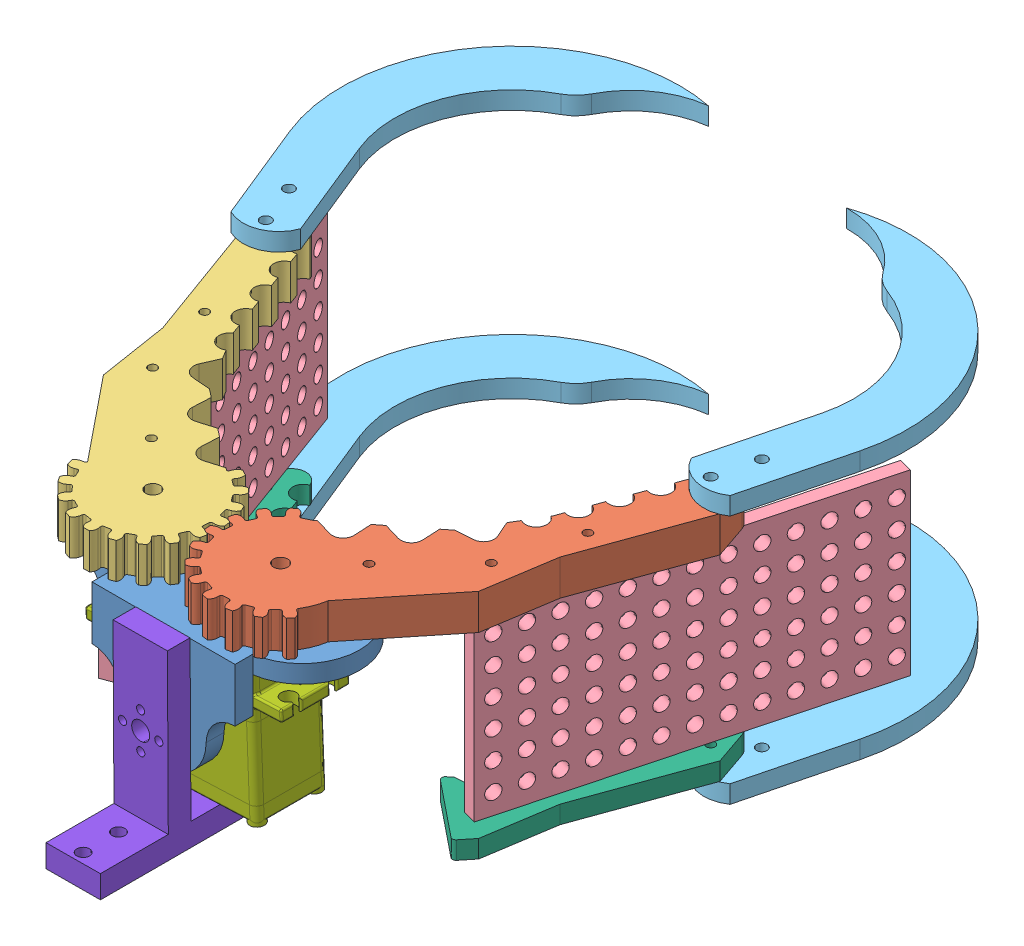
SolidWorks assembly NewGripper1, configuration Default. Lengths in mm.
Overall size (190.58 75 219.37).
13 component instances, 8 part files, 33 mates.
Components (placement in the parent):
- Gripper_Connector-1: Gripper_Connector [Default] at (155.1175 95.088 13.5) size (68 35 37)
- Gripper_Finger_Driver-1: Gripper_Finger_Driver [Default] at (52.3655 100.088 -111.0032) x (0.778613 0 0.627504) z (-0.627504 0 0.778613) size (41.13 10 113.29)
- Gripper_Finger_Driven-1: Gripper_Finger_Driven [Default] at (151.1675 100.088 -2.5) x (0.777386 0 -0.629024) z (0.629024 0 0.777386) size (41.12 10 113.36)
- SiftPlate-1: SiftPlate [Default] at (229.8315 75.088 -75.0884) x (-0.966695 0 -0.255932) z (0 -1 0) size (3.75 100 50)
- Finger_Extension-1: Finger_Extension [Default] at (106.6731 110.088 -78.6634) x (-0.37629 0 -0.926502) z (0.926502 0 -0.37629) size (81.26 5 73.02)
- Finger_Extension-2: Finger_Extension [Default] at (231.3429 115.088 -78.7502) x (0.245882 0 -0.9693) z (-0.9693 0 -0.245882) size (81.26 5 73.02)
- Gripper_Finger-1: Gripper_Finger [Default] at (202.8139 50.088 -0.0392) x (-0.778654 0 -0.627453) z (-0.627453 0 0.778654) size (35.99 5 61.76)
- SiftPlate-2: SiftPlate [Default] at (112.2054 75.088 -55.9482) x (0.938466 0 -0.345372) z (0 -1 0) size (3.75 100 50)
- Gripper_Finger-2: Gripper_Finger [Default] at (135.7476 45.088 -0.1523) x (0.774281 0 -0.632842) z (0.632842 0 0.774281) size (35.99 5 61.76)
- Finger_Extension-3: Finger_Extension [Default] at (106.6731 40.088 -78.6634) x (-0.37629 0 -0.926502) z (0.926502 0 -0.37629) size (81.26 5 73.02)
- Finger_Extension-4: Finger_Extension [Default] at (231.3429 45.088 -78.7502) x (0.245882 0 -0.9693) z (-0.9693 0 -0.245882) size (81.26 5 73.02)
- Servo 20kg elbow and gripper-1: Servo 20kg elbow and gripper [Default] at (176.4094 57.293 3.45) x (0.999206 0.039848 0) z (0 0 1) size (55.1 45.65 20.12)
- GripperArmBracket-1: GripperArmBracket [Default] at (167.6519 49.36 15.96) x (0 0 -1) z (0.999984 0.005574 0) size (55.88 50.8 15.24)
Mates (geometry in assembly coordinates):
- Concentric1: concentric aligned: circle of Gripper_Connector-1; circle of Gripper_Finger_Driver-1
- Coincident1: coincident anti-aligned: plane of Gripper_Connector-1 through (155.1175 100.088 -18.5) normal (0 1 0); plane of Gripper_Finger_Driver-1 through (52.3655 100.088 -111.0032) normal (0 -1 0)
- Concentric2: concentric aligned: circle of Gripper_Connector-1; circle of Gripper_Finger_Driven-1
- Coincident2: coincident anti-aligned: plane of Gripper_Connector-1 through (155.1175 100.088 -18.5) normal (0 1 0); plane of Gripper_Finger_Driven-1 through (151.1675 100.088 -2.5) normal (0 -1 0)
- GearMate2: gear = 4 : 4 mm: circle of Gripper_Finger_Driven-1; circle of Gripper_Finger_Driver-1
- Coincident17: coincident aligned: circle of Gripper_Finger_Driver-1; circle of SiftPlate-1
- Concentric12: concentric aligned: circle of Gripper_Finger_Driven-1; circle of Finger_Extension-1
- Coincident25: coincident anti-aligned: plane of Gripper_Finger_Driven-1 through (151.1675 110.088 -2.5) normal (0 1 0); plane of Finger_Extension-1 through (106.6731 110.088 -78.6634) normal (0 -1 0)
- Lock1: lock: unknown of Gripper_Finger_Driven-1; unknown of Finger_Extension-1
- Concentric13: concentric anti-aligned: circle of Gripper_Finger_Driver-1; circle of Finger_Extension-2
- Coincident27: coincident anti-aligned: plane of Gripper_Finger_Driver-1 through (52.3655 110.088 -111.0032) normal (0 1 0); plane of Finger_Extension-2 through (231.3429 110.088 -78.7502) normal (0 -1 0)
- Lock2: lock: unknown of Gripper_Finger_Driver-1; unknown of Finger_Extension-2
- Lock3: lock: unknown of SiftPlate-1; unknown of Finger_Extension-2
- Concentric14: concentric anti-aligned: circle of Gripper_Finger_Driver-1; circle of Gripper_Finger-1
- Coincident33: coincident anti-aligned: plane of SiftPlate-1 through (213.4098 50.088 -27.7134) normal (0 -1 0); plane of Gripper_Finger-1 through (229.5768 50.088 -84.2343) normal (0 1 0)
- Concentric15: concentric aligned: circle of Finger_Extension-2; circle of Gripper_Finger-1
- Concentric16: concentric aligned: circle of Gripper_Finger_Driven-1; circle of SiftPlate-2
- Coincident35: coincident anti-aligned: plane of Gripper_Finger_Driven-1 through (151.1675 100.088 -2.5) normal (0 -1 0); plane of SiftPlate-2 through (98.4561 100.088 -104.1667) normal (0 1 0)
- Lock4: lock: unknown of Gripper_Finger_Driven-1; unknown of SiftPlate-2
- Concentric17: concentric aligned: circle of Finger_Extension-1; circle of Gripper_Finger-2
- Coincident38: coincident anti-aligned: plane of SiftPlate-2 through (98.4561 50.088 -104.1667) normal (0 -1 0); plane of Gripper_Finger-2 through (108.4011 50.088 -84.1597) normal (0 1 0)
- Lock5: lock: unknown of SiftPlate-2; unknown of Gripper_Finger-2
- Concentric18: concentric aligned: circle of Gripper_Finger-2; circle of Finger_Extension-3
- Coincident40: coincident anti-aligned: plane of Gripper_Finger-2 through (108.4011 45.088 -84.1597) normal (0 -1 0); plane of Finger_Extension-3 through (106.6731 45.088 -78.6634) normal (0 1 0)
- Parallel9: parallel anti-aligned: plane of Finger_Extension-1 through (106.6731 110.088 -78.6634) normal (0 -1 0); plane of Finger_Extension-3 through (106.6731 45.088 -78.6634) normal (0 1 0)
- Concentric19: concentric aligned: circle of Finger_Extension-1; circle of Finger_Extension-3
- Concentric20: concentric aligned: circle of Gripper_Finger-1; circle of Finger_Extension-4
- Coincident45: coincident anti-aligned: plane of Gripper_Finger-1 through (229.5768 45.088 -84.2343) normal (0 -1 0); plane of Finger_Extension-4 through (231.3429 45.088 -78.7502) normal (0 1 0)
- Concentric21: concentric aligned: circle of Finger_Extension-2; circle of Finger_Extension-4
- Coincident52: coincident anti-aligned: plane of Gripper_Connector-1 through (155.1175 95.088 13.5) normal (0 0 -1); plane of Servo 20kg elbow and gripper-1 through (194.8296 98.5598 13.5) normal (0 0 1)
- Lock6: lock: unknown of Gripper_Connector-1; unknown of Servo 20kg elbow and gripper-1
- Concentric22: concentric aligned: circle of Gripper_Connector-1; circle of GripperArmBracket-1
- Coincident54: coincident anti-aligned: plane of Gripper_Connector-1 through (155.1175 95.088 18.5) normal (0 0 1); plane of GripperArmBracket-1 through (182.8563 55.7948 18.5) normal (0 0 -1)
